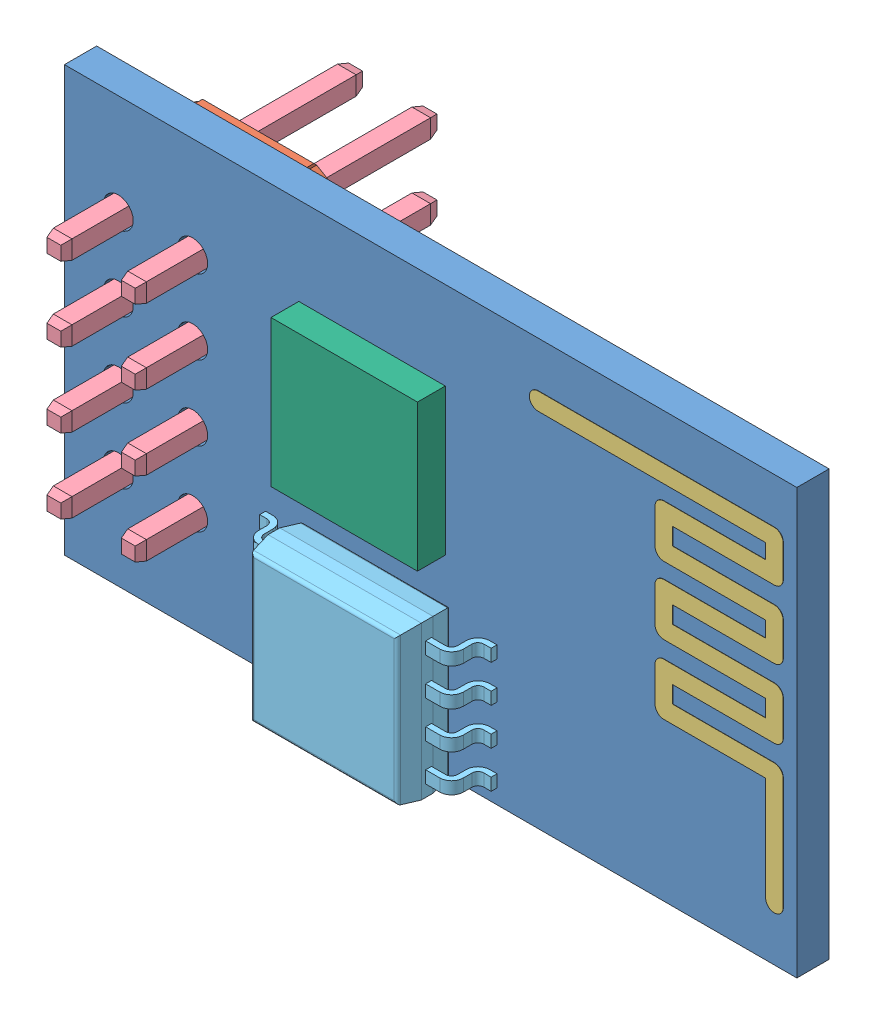
SolidWorks assembly ESP8266-ESP01, configuration Predeterminado. Lengths in mm.
Overall size (25 14.5 10.3).
14 component instances, 6 part files, 0 mates.
Components (placement in the parent):
- ESP8266-ESP01.stp-1: ESP8266-ESP01.stp [Predeterminado] at origin size (25 14.5 10.3)
  - Platine.stp-1: Platine.stp [Predeterminado] at origin size (25 14.5 1.1)
  - PinSockel.stp-1: PinSockel.stp [Predeterminado] at (1.8391 11.06 0) x (1 0 0) z (0 0 -1) size (5 10.16 2.5)
  - PCB_Antenna.stp-1: PCB_Antenna.stp [Predeterminado] at (1 16 0.81) x (0 -1 0) z (-1 0 0) size (11.4 0.04 8.67)
  - Pin_Stiftleiste.stp-1: Pin_Stiftleiste.stp [Predeterminado] at (1.8391 3.44 0) x (-1 0 0) z (0 0 -1) size (0.64 0.64 10.3)
  - Pin_Stiftleiste.stp-2: Pin_Stiftleiste.stp [Predeterminado] at (4.3791 3.44 0) x (-1 0 0) z (0 0 -1) size (0.64 0.64 10.3)
  - Pin_Stiftleiste.stp-3: Pin_Stiftleiste.stp [Predeterminado] at (1.8391 5.98 0) x (-1 0 0) z (0 0 -1) size (0.64 0.64 10.3)
  - Pin_Stiftleiste.stp-4: Pin_Stiftleiste.stp [Predeterminado] at (4.3791 5.98 0) x (-1 0 0) z (0 0 -1) size (0.64 0.64 10.3)
  - Pin_Stiftleiste.stp-5: Pin_Stiftleiste.stp [Predeterminado] at (1.8391 8.52 0) x (-1 0 0) z (0 0 -1) size (0.64 0.64 10.3)
  - Pin_Stiftleiste.stp-6: Pin_Stiftleiste.stp [Predeterminado] at (4.3791 8.52 0) x (-1 0 0) z (0 0 -1) size (0.64 0.64 10.3)
  - Pin_Stiftleiste.stp-7: Pin_Stiftleiste.stp [Predeterminado] at (1.8391 11.06 0) x (-1 0 0) z (0 0 -1) size (0.64 0.64 10.3)
  - Pin_Stiftleiste.stp-8: Pin_Stiftleiste.stp [Predeterminado] at (4.3791 11.06 0) x (-1 0 0) z (0 0 -1) size (0.64 0.64 10.3)
  - SerialFlashMem.stp-1: SerialFlashMem.stp [Predeterminado] at (8.2 0.1 1.1) size (7.9 5.23 1.97)
  - ESP8266EX.stp-1: ESP8266EX.stp [Predeterminado] at (8 6.5 1.1) size (5 5 0.95)
